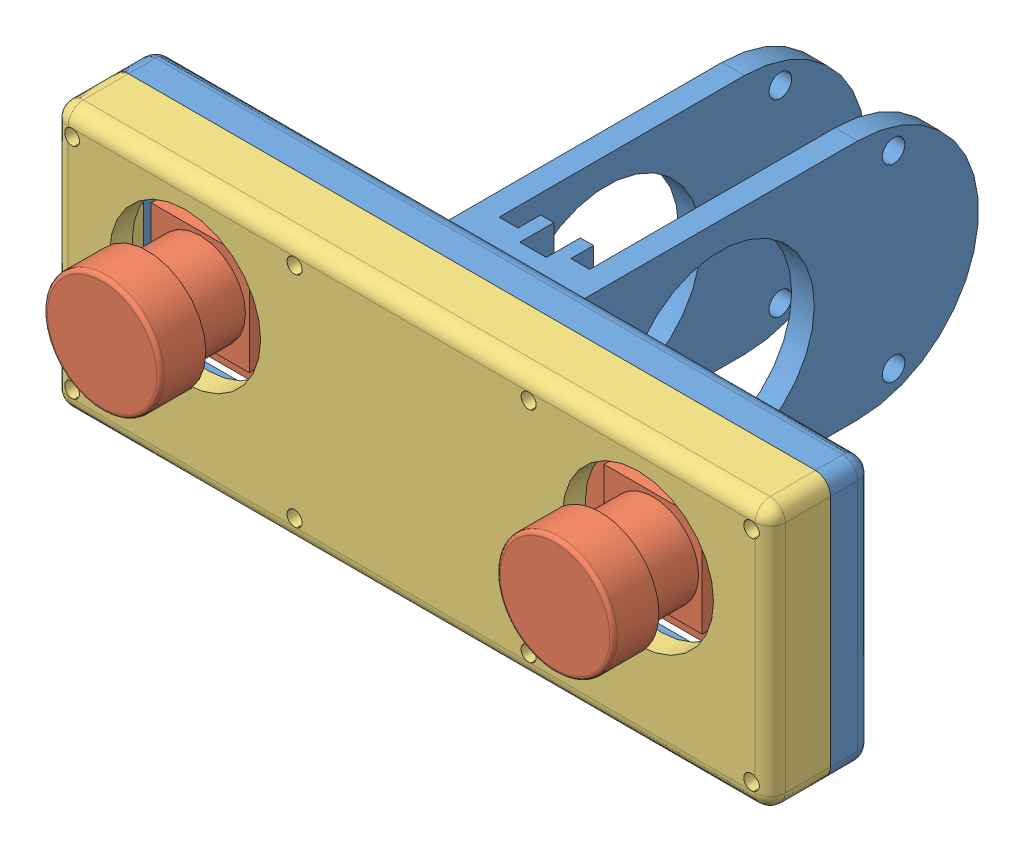
SolidWorks assembly cam_assembly, configuration Default. Lengths in mm.
Overall size (95 35 77.1).
3 component instances, 3 part files, 6 mates.
Components (placement in the parent):
- holder-1: holder [Default] at (28.4846 50.0392 73.6492) size (95 35 58.1)
- IMX219-83 Stereo Camera-1: IMX219-83 Stereo Camera [Default] at (28.4846 50.0392 75.2492) size (85 24 23)
- CAM_COVER-3: CAM_COVER [Default] at (41.1275 21.2078 84.2492) size (95 35 8)
Mates (geometry in assembly coordinates):
- Concentric1: concentric aligned: circle of cam-1; cylinder of stereo_camera-1 through (-12.0154 60.0392 75.2492) axis (0 0 1) radius 1.1
- Concentric2: concentric aligned: cylinder of holder-1 through (17.9846 46.5392 73.6492) axis (0 0 1) radius 1.1; cylinder of stereo_camera-1 through (17.9846 46.5392 75.2492) axis (0 0 1) radius 1.1
- Coincident1: coincident anti-aligned: plane of holder-1 through (28.4846 50.0392 75.2492) normal (0 0 1); plane of stereo_camera-1 through (28.4846 50.0392 75.2492) normal (0 0 -1)
- Concentric4: concentric anti-aligned: cylinder of holder-1 through (-16.5154 64.5392 21.1492) axis (0 0 1) radius 1; cylinder of CAM_COVER-3 through (-16.5154 64.5392 87.2492) axis (0 0 -1) radius 1
- Concentric5: concentric anti-aligned: cylinder of holder-1 through (73.4846 64.5392 21.1492) axis (0 0 1) radius 1; cylinder of CAM_COVER-3 through (73.4846 64.5392 87.2492) axis (0 0 -1) radius 1
- Coincident6: coincident anti-aligned: plane of holder-1 through (28.4846 50.0392 79.2492) normal (0 0 1); plane of CAM_COVER-3 through (41.1275 21.2078 79.2492) normal (0 0 -1)
